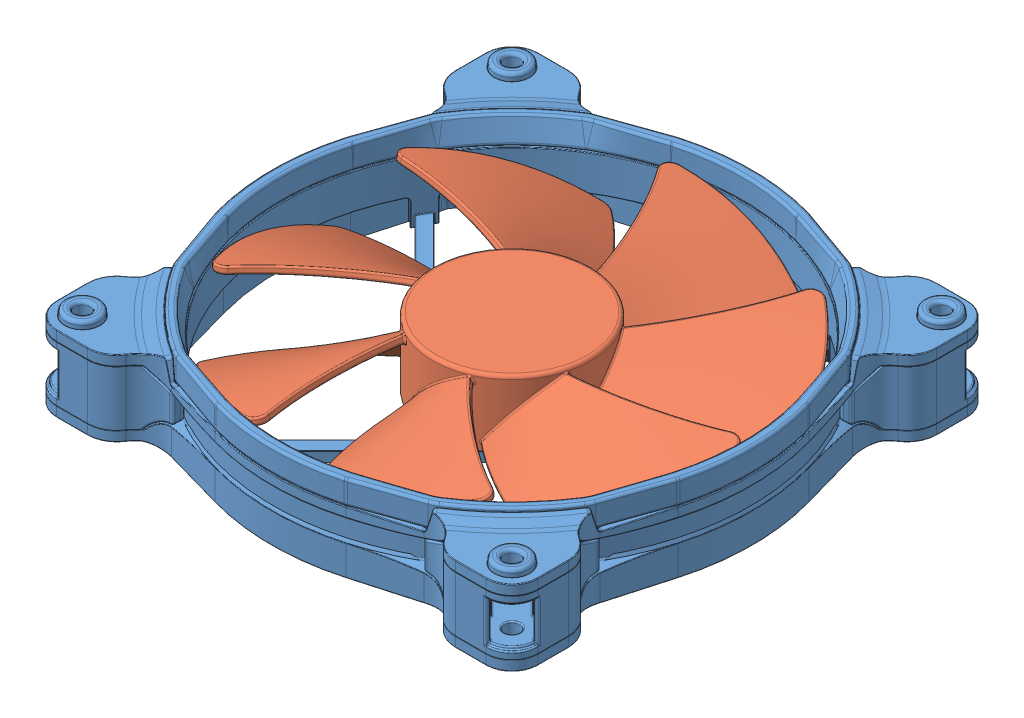
SolidWorks assembly Corsair Air Series SP140, configuration Default. Lengths in mm.
Overall size (134.4 24.36 134.4).
2 component instances, 2 part files, 2 mates.
Components (placement in the parent):
- Corsair Air Series 140 Fan Frame-1: Corsair Air Series 140 Fan Frame [Default] at origin size (134.4 24.36 134.4)
- Corsair Air Series SP140 Fanblade-1: Corsair Air Series SP140 Fanblade [Default] at (0 3.84 0) size (128.69 19.94 129.46)
Mates (geometry in assembly coordinates):
- Coincident1: coincident aligned: plane of Corsair Air Series 140 Fan Frame-1 through (0 23.04 68.88) normal (0 1 0); plane of Corsair Air Series SP140 Fanblade-1 through (0 23.04 0) normal (0 1 0)
- Concentric1: concentric aligned: cylinder of Corsair Air Series 140 Fan Frame-1 through (0 0 0) axis (0 -1 0) radius 64.32; cylinder of Corsair Air Series SP140 Fanblade-1 through (0 23.04 0) axis (0 -1 0) radius 22.08
